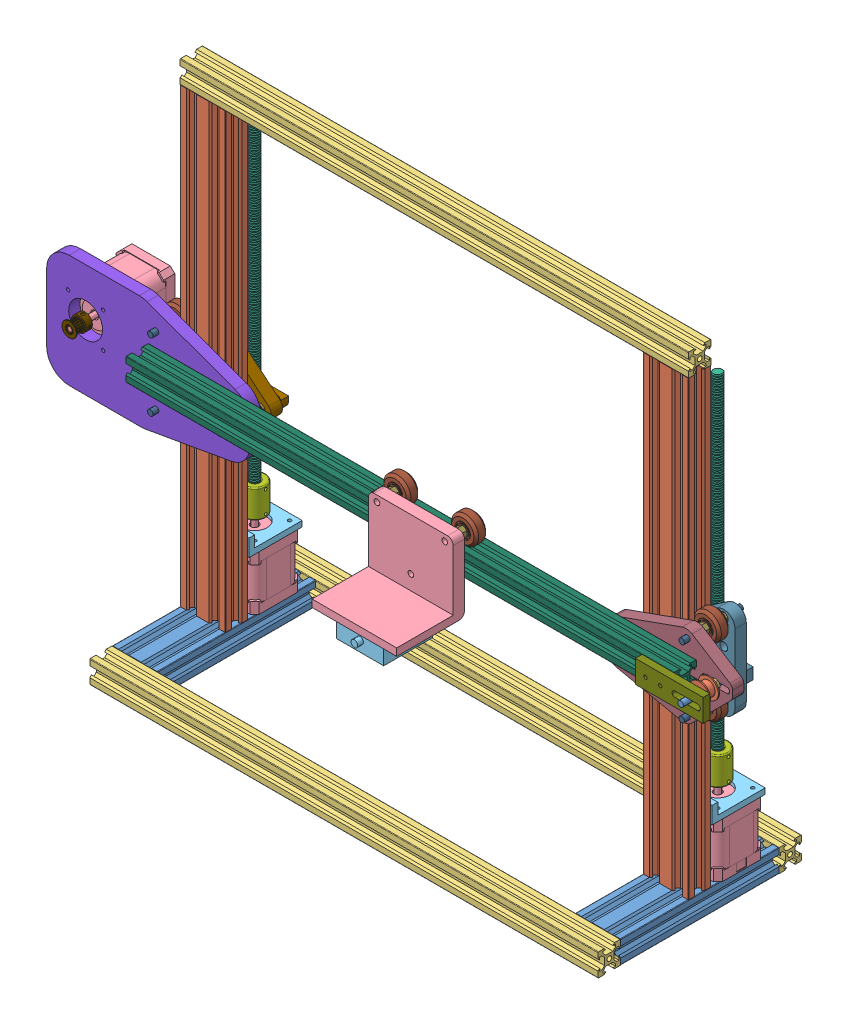
SolidWorks assembly Assembly_Design_1, configuration Default. Lengths in mm.
Overall size (607.25 440 192.3).
70 component instances, 26 part files, 187 mates.
Components (placement in the parent):
- V_Slot_40x20_140mm-1: V_Slot_40x20_140mm [Default] at (9.5 10 -140) x (0 -1 0) z (0 0 1) size (20 40 140)
- V_Slot_40x20_400mm-1: V_Slot_40x20_400mm [Default] at (9.5 420 -70) x (0 0 -1) z (0 -1 0) size (20 40 400)
- V_Slot_20x20_450mm-1: V_Slot_20x20_450mm [Default] at (-0.5 430 -70) x (0 0 -1) z (1 0 0) size (20 20 450)
- V_Slot_40x20_400mm-2: V_Slot_40x20_400mm [Default] at (419.5 20 -70) x (0 0 1) z (0 1 0) size (20 40 400)
- V_Slot_40x20_140mm-2: V_Slot_40x20_140mm [Default] at (439.5 10 -140) x (0 1 0) z (0 0 1) size (20 40 140)
- V_Slot_20x20_450mm-2: V_Slot_20x20_450mm [Default] at (449.5 10 10) x (0 0 1) z (-1 0 0) size (20 20 450)
- V_Slot_20x20_450mm-3: V_Slot_20x20_450mm [Default] at (-0.5 10 -150) x (0 0 -1) z (1 0 0) size (20 20 450)
- Stepper_Motor_17HS19-2004S1-1: Stepper_Motor_17HS19-2004S1 [Predeterminado] at (19.5 44 -106) x (1 0 0) z (0 1 0) size (42 42 72)
- stepper_motor_mounting_bracket-1: stepper_motor_mounting_bracket [Default] at (19.5 68 -106) x (-1 0 0) z (0 1 0) size (42 47 15)
- Stepper_Motor_17HS19-2004S1-2: Stepper_Motor_17HS19-2004S1 [Predeterminado] at (429.5 44 -106) x (-1 0 0) z (0 1 0) size (42 42 72)
- stepper_motor_mounting_bracket-2: stepper_motor_mounting_bracket [Default] at (429.5 68 -106) x (-1 0 0) z (0 1 0) size (42 47 15)
- LeadScrew 8mm x 2mmPitch-1: LeadScrew 8mm x 2mmPitch [Default] at (429.5 92 -106) x (0.998698 0 -0.051019) z (0 -1 0) size (9.24 8 303.06)
- Coupling_Shaft_5x8-1: Coupling_Shaft_5x8 [Default] at (429.5 79.5 -106) x (0.999828 0 -0.01857) z (0.01857 0 0.999828) size (19 25 19)
- LeadScrew 8mm x 2mmPitch-2: LeadScrew 8mm x 2mmPitch [Default] at (19.5 92 -106) x (1 0 0) z (0 -1 0) size (9.24 8 303.06)
- Coupling_Shaft_5x8-2: Coupling_Shaft_5x8 [Default] at (19.5 79.5 -106) x (0.999319 0 -0.036886) z (0.036886 0 0.999319) size (19 25 19)
- leftbeam_wheel_mount_front-2: leftbeam_wheel_mount_front [Default] at (-107.5 151.5377 -58.8) x (1 0 0) z (0 -1 0) size (180 10 100)
- Stepper_Motor_17HS19-2004S1-4: Stepper_Motor_17HS19-2004S1 [Predeterminado] at (-73 209.0377 -82.8) size (42 42 72)
- leftbeam_wheel_mount_back-2: leftbeam_wheel_mount_back [Default] at (-21 158.5012 -91) x (1 0 0) z (0 -1 0) size (80 40 83.06)
- Wheel_mount_rod_for_brackets-1: Wheel_mount_rod_for_brackets [Default] at (-10.7 231.5377 -96) x (-0.970108 -0.242673 0) z (-0.242673 0.970108 0) size (5 52.2 5)
- Wheel_mount_rod_for_brackets-2: Wheel_mount_rod_for_brackets [Default] at (-10.7 171.5377 -96) x (-0.232708 0.972547 0) z (0.972547 0.232708 0) size (5 52.2 5)
- Wheel_mount_rod_for_brackets-3: Wheel_mount_rod_for_brackets [Default] at (49.8 186.5377 -96) x (-0.732499 0.680769 0) z (0.680769 0.732499 0) size (5 52.2 5)
- V_Slot_Wheel_OD24xID5-1: V_Slot_Wheel_OD24xID5 [Default] at (-10.7 231.5377 -69.9) x (0.993327 -0.115336 0) z (0 0 1) size (24 24 10.2)
- M5 Hex nut-1: M5 Hex nut [Default] at (-10.7 231.5377 -61.8) x (0.939693 -0.34202 0) z (0.34202 0.939693 0) size (9.01 6.7 7.8)
- M5 Hex nut-2: M5 Hex nut [Default] at (-10.7 231.5377 -78) x (0.939693 -0.34202 0) z (-0.34202 -0.939693 0) size (9.01 6.7 7.8)
- M5 Hex nut-3: M5 Hex nut [Default] at (-10.7 171.5377 -61.8) x (0 -1 0) z (1 0 0) size (9.01 6.7 7.8)
- M5 Hex nut-4: M5 Hex nut [Default] at (-10.7 171.5377 -78) x (0 -1 0) z (1 0 0) size (9.01 6.7 7.8)
- V_Slot_Wheel_OD24xID5-2: V_Slot_Wheel_OD24xID5 [Default] at (-10.7 171.5377 -69.9) x (0.998331 -0.057756 0) z (0 0 1) size (24 24 10.2)
- M5 Hex nut-5: M5 Hex nut [Default] at (49.8 186.5377 -78) x (0.866025 -0.5 0) z (-0.5 -0.866025 0) size (9.01 6.7 7.8)
- M5 Hex nut-6: M5 Hex nut [Default] at (49.8 186.5377 -61.8) x (0.866025 -0.5 0) z (0.5 0.866025 0) size (9.01 6.7 7.8)
- V_Slot_Wheel_OD24xID5-3: V_Slot_Wheel_OD24xID5 [Default] at (49.8 186.5377 -69.9) x (0.999874 0.01588 0) z (0 0 1) size (24 24 10.2)
- rightbeam_wheel_mount_front-1: rightbeam_wheel_mount_front [Default] at (499.75 204.3878 -58.8) size (110 73.04 10)
- rightbeam_wheels_mount _back-1: rightbeam_wheels_mount _back [Default] at (469.75 209.0377 -91) size (80.5 81.06 40)
- Wheel_mount_rod_for_brackets-4: Wheel_mount_rod_for_brackets [Default] at (459.75 231.5377 -96) x (0.11149 -0.993766 0) z (-0.993766 -0.11149 0) size (5 52.2 5)
- Wheel_mount_rod_for_brackets-5: Wheel_mount_rod_for_brackets [Default] at (399.25 186.5377 -96) x (-0.923728 -0.383049 0) z (-0.383049 0.923728 0) size (5 52.2 5)
- Wheel_mount_rod_for_brackets-6: Wheel_mount_rod_for_brackets [Default] at (459.75 171.5377 -96) x (-0.923728 -0.383049 0) z (-0.383049 0.923728 0) size (5 52.2 5)
- M5 Hex nut-7: M5 Hex nut [Default] at (459.75 171.5377 -78) x (0.965926 -0.258819 0) z (-0.258819 -0.965926 0) size (9.01 6.7 7.8)
- M5 Hex nut-8: M5 Hex nut [Default] at (459.75 171.5377 -61.8) x (0.965926 -0.258819 0) z (-0.258819 -0.965926 0) size (9.01 6.7 7.8)
- M5 Hex nut-9: M5 Hex nut [Default] at (399.25 186.5377 -61.8) x (0.941742 0.336336 0) z (0.336336 -0.941742 0) size (9.01 6.7 7.8)
- M5 Hex nut-10: M5 Hex nut [Default] at (399.25 186.5377 -78) x (0.941742 0.336336 0) z (0.336336 -0.941742 0) size (9.01 6.7 7.8)
- M5 Hex nut-11: M5 Hex nut [Default] at (459.75 231.5377 -78) x (0.941742 0.336336 0) z (-0.336336 0.941742 0) size (9.01 6.7 7.8)
- M5 Hex nut-12: M5 Hex nut [Default] at (459.75 231.5377 -61.8) x (0.941742 0.336336 0) z (0.336336 -0.941742 0) size (9.01 6.7 7.8)
- V_Slot_Wheel_OD24xID5-4: V_Slot_Wheel_OD24xID5 [Default] at (459.75 231.5377 -69.9) x (0.615703 0.787979 0) z (0 0 1) size (24 24 10.2)
- V_Slot_Wheel_OD24xID5-5: V_Slot_Wheel_OD24xID5 [Default] at (459.75 171.5377 -69.9) x (0.637684 0.770298 0) z (0 0 1) size (24 24 10.2)
- V_Slot_Wheel_OD24xID5-6: V_Slot_Wheel_OD24xID5 [Default] at (399.25 186.5377 -69.9) x (0.99333 -0.115309 0) z (0 0 1) size (24 24 10.2)
- V_Slot_20x20_485-1: V_Slot_20x20_485 [Default] at (467.75 209.0377 -38.8) x (0 0 1) z (-1 0 0) size (20 20 485)
- right_pulley_wheel_mount-1: right_pulley_wheel_mount [Default] at (439.75 199.0377 -28.8) size (60 20 6)
- LeadScrew Nut 8mm x 2mmPitch-1: LeadScrew Nut 8mm x 2mmPitch [Default] at (429.5 166.4718 -106) x (-1 0 0) z (0 -1 0) size (22 22 16.05)
- LeadScrew Nut 8mm x 2mmPitch-2: LeadScrew Nut 8mm x 2mmPitch [Default] at (19.5 168.5012 -106) x (-1 0 0) z (0 -1 0) size (22 22 16.05)
- 16 teeth pulley GT2 6mm ASSEMBLY PART-1: 16 teeth pulley GT2 6mm ASSEMBLY PART [По умолчанию] at (-73.2117 209.4463 -27.2) x (-0.994801 0.101836 0) z (0 0 -1) size (13.17 13.17 14.1)
- 5x46mm_rod-1: 5x46mm_rod [Default] at (484.75 209.0377 -17.8) x (0.599612 0.800291 0) z (-0.800291 0.599612 0) size (5 46 5)
- POWGE 2GT idler 20T B5-1: POWGE 2GT idler 20T B5 [Default] at (484.75 209.0377 -38.8) x (0 0 1) z (0.346507 -0.938047 0) size (9 18 18)
- M5 Hex nut_5.5mm-1: M5 Hex nut_5.5mm [Default] at (484.75 209.0377 -31.55) x (1 0 0) z (0 1 0) size (9.01 6.2 7.8)
- M5 Hex nut_5.5mm-2: M5 Hex nut_5.5mm [Default] at (484.75 209.0377 -46.05) x (1 0 0) z (0 1 0) size (9.01 6.2 7.8)
- centre_laser_mount-1: centre_laser_mount [Default] at (246.0327 207.4577 -27.7) x (1 0 0) z (0 -1 0) size (75 60 65)
- V_Slot_Wheel_OD24xID5-7: V_Slot_Wheel_OD24xID5 [Default] at (276.0327 229.4577 -38.8) x (0.900063 0.43576 0) z (0 0 -1) size (24 24 10.2)
- V_Slot_Wheel_OD24xID5-8: V_Slot_Wheel_OD24xID5 [Default] at (216.0327 229.4577 -38.8) x (0.900063 0.43576 0) z (0 0 -1) size (24 24 10.2)
- V_Slot_Wheel_OD24xID5-9: V_Slot_Wheel_OD24xID5 [Default] at (246.0327 189.4577 -38.8) x (0.900063 0.43576 0) z (0 0 -1) size (24 24 10.2)
- M5 Hex nut-13: M5 Hex nut [Default] at (216.0327 229.4577 -30.7) x (0 -1 0) z (1 0 0) size (9.01 6.7 7.8)
- M5 Hex nut-14: M5 Hex nut [Default] at (246.0327 189.4577 -30.7) x (0 -1 0) z (1 0 0) size (9.01 6.7 7.8)
- M5 Hex nut-15: M5 Hex nut [Default] at (276.0327 229.4577 -30.7) x (0 1 0) z (1 0 0) size (9.01 6.7 7.8)
- heavy hex flange screw_am-2: heavy hex flange screw_am [PreviewCfg] at (246.0327 189.4577 -49.7) x (0 0 1) z (0.383049 -0.923728 0) size (40.8 11.8 11.8) (hidden)
- heavy hex flange screw_am-3: heavy hex flange screw_am [PreviewCfg] at (276.0327 229.4577 -49.7) x (0 0 1) z (0.383049 -0.923728 0) size (40.8 11.8 11.8) (hidden)
- heavy hex flange screw_am-4: heavy hex flange screw_am [PreviewCfg] at (216.0327 229.4577 -49.7) x (0 0 1) z (0.383049 -0.923728 0) size (40.8 11.8 11.8) (hidden)
- flat washer regular_am-1: flat washer regular_am [PreviewCfg] at (246.0327 189.4577 -17.7) x (0 0 -1) z (0.380789 -0.924662 0) size (1.75 15 15) (hidden)
- flat washer regular_am-2: flat washer regular_am [PreviewCfg] at (276.0327 229.4577 -17.7) x (0 0 -1) z (0.383049 -0.923728 0) size (1.75 15 15) (hidden)
- flat washer regular_am-3: flat washer regular_am [PreviewCfg] at (216.0327 229.4577 -17.7) x (0 0 -1) z (0.383049 -0.923728 0) size (1.75 15 15) (hidden)
- hex flange nut_am-1: hex flange nut_am [PreviewCfg] at (276.0327 229.4577 -10.95) x (0.923728 0.383049 0) z (0 0 1) size (11.8 11.8 5) (hidden)
- hex flange nut_am-2: hex flange nut_am [PreviewCfg] at (246.0327 189.4577 -10.95) x (0.923728 0.383049 0) z (0 0 1) size (11.8 11.8 5) (hidden)
- hex flange nut_am-3: hex flange nut_am [PreviewCfg] at (216.0327 229.4577 -10.95) x (0.923728 0.383049 0) z (0 0 1) size (11.8 11.8 5) (hidden)
- SEN0366_DFRobot_makeshift-1: SEN0366_DFRobot_makeshift [Default] at (225.0327 151.9577 -15.7) x (0 0 1) z (-1 0 0) size (48 18 42)
Mates (geometry in assembly coordinates):
- Coincident5: coincident: point of V_Slot_40x20_140mm-1
- Parallel1: parallel anti-aligned: plane of V_Slot_40x20_140mm-1 through (9.5 0 0) normal (0 -1 0)
- Parallel2: parallel aligned: plane of V_Slot_40x20_140mm-1 through (39.5 10 0) normal (1 0 0)
- Coincident12: coincident anti-aligned: plane of V_Slot_40x20_140mm-1 through (9.5 20 0) normal (0 1 0); plane of V_Slot_40x20_400mm-1 through (9.5 20 -70) normal (0 -1 0)
- Parallel5: parallel aligned: plane of V_Slot_40x20_140mm-1 through (-0.5 10 0) normal (-1 0 0); plane of V_Slot_40x20_400mm-1 through (-0.5 20 -70) normal (-1 0 0)
- Coincident15: coincident aligned: plane of V_Slot_40x20_140mm-1 through (-0.5 10 0) normal (-1 0 0); plane of V_Slot_40x20_400mm-1 through (-0.5 20 -70) normal (-1 0 0)
- Distance2: distance = 60 mm aligned: plane of V_Slot_40x20_400mm-1 through (9.5 20 -80) normal (0 0 -1); plane of V_Slot_40x20_140mm-1 through (9.5 10 -140) normal (0 0 -1)
- Coincident17: coincident anti-aligned: plane of V_Slot_40x20_400mm-1 through (9.5 420 -70) normal (0 1 0); plane of V_Slot_20x20_450mm-1 through (449.5 420 -65.42) normal (0 -1 0)
- Parallel6: parallel anti-aligned: plane of V_Slot_40x20_400mm-1 through (-0.5 20 -70) normal (-1 0 0); plane of V_Slot_20x20_450mm-1 through (449.5 439.5 -79.5) normal (1 0 0)
- Coincident19: coincident aligned: plane of V_Slot_40x20_400mm-1 through (-0.5 20 -70) normal (-1 0 0); plane of V_Slot_20x20_450mm-1 through (-0.5 439.5 -79.5) normal (-1 0 0)
- Coincident20: coincident aligned: plane of V_Slot_40x20_400mm-1 through (9.5 20 -80) normal (0 0 -1); plane of V_Slot_20x20_450mm-1 through (449.5 420.5 -80) normal (0 0 -1)
- Coincident21: coincident anti-aligned: plane of V_Slot_20x20_450mm-1 through (449.5 420 -65.42) normal (0 -1 0); plane of V_Slot_40x20_400mm-2 through (419.5 420 -70) normal (0 1 0)
- Parallel7: parallel anti-aligned: plane of V_Slot_20x20_450mm-1 through (449.5 439.5 -79.5) normal (1 0 0); plane of V_Slot_40x20_400mm-2 through (409.5 420 -70) normal (-1 0 0)
- Coincident23: coincident aligned: plane of V_Slot_20x20_450mm-1 through (449.5 439.5 -79.5) normal (1 0 0); plane of V_Slot_40x20_400mm-2 through (449.5 420 -70) normal (1 0 0)
- Coincident24: coincident aligned: plane of V_Slot_20x20_450mm-1 through (449.5 420.5 -60) normal (0 0 1); plane of V_Slot_40x20_400mm-2 through (419.5 420 -60) normal (0 0 1)
- Coincident25: coincident anti-aligned: plane of V_Slot_40x20_400mm-2 through (419.5 20 -70) normal (0 -1 0); plane of V_Slot_40x20_140mm-2 through (439.5 20 0) normal (0 1 0)
- Coincident26: coincident aligned: plane of V_Slot_40x20_400mm-2 through (409.5 420 -70) normal (-1 0 0); plane of V_Slot_40x20_140mm-2 through (409.5 10 0) normal (-1 0 0)
- Distance3: distance = 60 mm aligned: plane of V_Slot_40x20_400mm-2 through (419.5 420 -80) normal (0 0 -1); plane of V_Slot_40x20_140mm-2 through (439.5 10 -140) normal (0 0 -1)
- Coincident28: coincident anti-aligned: plane of V_Slot_40x20_140mm-2 through (439.5 10 0) normal (0 0 1); plane of V_Slot_20x20_450mm-2 through (-0.5 19.5 0) normal (0 0 -1)
- Coincident29: coincident aligned: plane of V_Slot_40x20_140mm-1 through (-0.5 10 0) normal (-1 0 0); plane of V_Slot_20x20_450mm-2 through (-0.5 19.5 19.5) normal (-1 0 0)
- Coincident30: coincident aligned: plane of V_Slot_40x20_140mm-1 through (9.5 20 0) normal (0 1 0); plane of V_Slot_20x20_450mm-2 through (-0.5 20 5.42) normal (0 1 0)
- Coincident31: coincident anti-aligned: plane of V_Slot_40x20_140mm-2 through (439.5 10 -140) normal (0 0 -1); plane of V_Slot_20x20_450mm-3 through (449.5 19.5 -140) normal (0 0 1)
- Coincident32: coincident aligned: plane of V_Slot_40x20_140mm-2 through (449.5 10 0) normal (1 0 0); plane of V_Slot_20x20_450mm-3 through (449.5 19.5 -159.5) normal (1 0 0)
- Coincident33: coincident aligned: plane of V_Slot_40x20_140mm-2 through (439.5 20 0) normal (0 1 0); plane of V_Slot_20x20_450mm-3 through (449.5 20 -145.42) normal (0 1 0)
- Coincident34: coincident anti-aligned: plane of V_Slot_40x20_140mm-1 through (9.5 20 0) normal (0 1 0); plane of Stepper_Motor_17HS19-2004S1-1 through (19.5 20 -106) normal (0 -1 0)
- Parallel8: parallel aligned: plane of V_Slot_40x20_140mm-1 through (-0.5 10 0) normal (-1 0 0); plane of Stepper_Motor_17HS19-2004S1-1 through (-1.5 68 -123) normal (-1 0 0)
- Coincident36: coincident anti-aligned: plane of Stepper_Motor_17HS19-2004S1-1 through (19.5 68 -106) normal (0 1 0); plane of stepper_motor_mounting_bracket-1 through (19.5 68 -106) normal (0 -1 0)
- Concentric1: concentric aligned: circle of Stepper_Motor_17HS19-2004S1-1; circle of stepper_motor_mounting_bracket-1
- Coincident38: coincident anti-aligned: plane of V_Slot_40x20_400mm-1 through (9.5 20 -80) normal (0 0 -1); plane of stepper_motor_mounting_bracket-1 through (40.5 73 -80) normal (0 0 1)
- Distance4: distance = 1 mm aligned: plane of stepper_motor_mounting_bracket-1 through (40.5 73 -85) normal (1 0 0); plane of V_Slot_40x20_400mm-1 through (39.5 20 -70) normal (1 0 0)
- Coincident40: coincident anti-aligned: plane of V_Slot_40x20_140mm-2 through (439.5 20 0) normal (0 1 0); plane of Stepper_Motor_17HS19-2004S1-2 through (429.5 20 -106) normal (0 -1 0)
- Parallel9: parallel anti-aligned: plane of V_Slot_40x20_400mm-2 through (419.5 420 -80) normal (0 0 -1); plane of Stepper_Motor_17HS19-2004S1-2 through (412.5 68 -85) normal (0 0 1)
- Coincident42: coincident anti-aligned: plane of Stepper_Motor_17HS19-2004S1-2 through (429.5 68 -106) normal (0 1 0); plane of stepper_motor_mounting_bracket-2 through (429.5 68 -106) normal (0 -1 0)
- Concentric2: concentric aligned: circle of Stepper_Motor_17HS19-2004S1-2; circle of stepper_motor_mounting_bracket-2
- Coincident44: coincident anti-aligned: plane of V_Slot_40x20_400mm-2 through (419.5 420 -80) normal (0 0 -1); plane of stepper_motor_mounting_bracket-2 through (450.5 73 -80) normal (0 0 1)
- Distance5: distance = 1 mm aligned: plane of stepper_motor_mounting_bracket-2 through (450.5 73 -85) normal (1 0 0); plane of V_Slot_40x20_400mm-2 through (449.5 420 -70) normal (1 0 0)
- Concentric3: concentric aligned: cylinder of Stepper_Motor_17HS19-2004S1-2 through (429.5 92 -106) axis (0 -1 0) radius 2.5; cylinder of Coupling_Shaft_5x8-1 through (429.5 104.5 -106) axis (0 -1 0) radius 2.5
- Coincident46: coincident aligned: plane of Stepper_Motor_17HS19-2004S1-2 through (429.5 92 -106) normal (0 1 0); plane of Coupling_Shaft_5x8-1 through (429.5 92 -106) normal (0 1 0)
- Lock1: lock: unknown of stepper_motor_mounting_bracket-2; unknown of Coupling_Shaft_5x8-1
- Concentric4: concentric anti-aligned: cylinder of LeadScrew 8mm x 2mmPitch-1 through (429.5 392 -106) axis (0 -1 0) radius 4; cylinder of Coupling_Shaft_5x8-1 through (429.5 92 -106) axis (0 1 0) radius 4
- Coincident47: coincident anti-aligned: plane of LeadScrew 8mm x 2mmPitch-1 through (429.5 92 -106) normal (0 -1 0); plane of Coupling_Shaft_5x8-1 through (429.5 92 -106) normal (0 1 0)
- Lock2: lock: unknown of LeadScrew 8mm x 2mmPitch-1; unknown of Coupling_Shaft_5x8-1
- Concentric5: concentric aligned: cylinder of Stepper_Motor_17HS19-2004S1-1 through (19.5 92 -106) axis (0 -1 0) radius 2.5; cylinder of Coupling_Shaft_5x8-2 through (19.5 104.5 -106) axis (0 -1 0) radius 2.5
- Coincident48: coincident aligned: plane of Stepper_Motor_17HS19-2004S1-1 through (19.5 92 -106) normal (0 1 0); plane of Coupling_Shaft_5x8-2 through (19.5 92 -106) normal (0 1 0)
- Lock3: lock: unknown of stepper_motor_mounting_bracket-1; unknown of Coupling_Shaft_5x8-2
- Coincident49: coincident anti-aligned: plane of LeadScrew 8mm x 2mmPitch-2 through (19.5 92 -106) normal (0 -1 0); plane of Coupling_Shaft_5x8-2 through (19.5 92 -106) normal (0 1 0)
- Concentric6: concentric anti-aligned: cylinder of LeadScrew 8mm x 2mmPitch-2 through (19.5 392 -106) axis (0 -1 0) radius 4; cylinder of Coupling_Shaft_5x8-2 through (19.5 92 -106) axis (0 1 0) radius 4
- Lock4: lock: unknown of LeadScrew 8mm x 2mmPitch-2; unknown of Coupling_Shaft_5x8-2
- Parallel15: parallel anti-aligned: plane of V_Slot_40x20_400mm-1 through (9.5 20 -60) normal (0 0 1); plane of leftbeam_wheel_mount_front-2 through (-107.5 151.5377 -58.8) normal (0 0 -1)
- Concentric13: concentric aligned: cylinder of leftbeam_wheel_mount_front-2 through (-73 209.0377 -48.8) axis (0 0 -1) radius 15; cylinder of Stepper_Motor_17HS19-2004S1-4 through (-73 209.0377 -34.8) axis (0 0 -1) radius 2.5
- Parallel16: parallel aligned: plane of leftbeam_wheel_mount_front-2 through (-107.5 151.5377 -48.8) normal (-1 0 0); plane of Stepper_Motor_17HS19-2004S1-4 through (-94 209.0377 -106.802) normal (-1 0 0)
- Concentric14: concentric anti-aligned: cylinder of LeadScrew 8mm x 2mmPitch-2 through (19.5 392 -106) axis (0 -1 0) radius 4; cylinder of leftbeam_wheel_mount_back-2 through (19.5 158.5012 -106) axis (0 1 0) radius 5.25
- Concentric15: concentric aligned: circle of leftbeam_wheel_mount_front-2; circle of leftbeam_wheel_mount_back-2
- Concentric16: concentric anti-aligned: cylinder of Wheel_mount_rod_for_brackets-1 through (-10.7 231.5377 -43.8) axis (0 0 -1) radius 2.5; cylinder of V_Slot_Wheel_OD24xID5-1 through (-10.7 231.5377 -75) axis (0 0 1) radius 2.5
- Concentric17: concentric aligned: circle of leftbeam_wheel_mount_front-2; circle of leftbeam_wheel_mount_back-2
- Concentric18: concentric anti-aligned: cylinder of Wheel_mount_rod_for_brackets-1 through (-10.7 231.5377 -43.8) axis (0 0 -1) radius 2.5; circle of M5 Hex nut-1
- Coincident67: coincident anti-aligned: plane of V_Slot_Wheel_OD24xID5-1 through (-10.7 231.5377 -64.8) normal (0 0 1); plane of M5 Hex nut-1 through (-10.7 231.5377 -64.8) normal (0 0 -1)
- Concentric20: concentric anti-aligned: cylinder of Wheel_mount_rod_for_brackets-1 through (-10.7 231.5377 -43.8) axis (0 0 -1) radius 2.5; circle of M5 Hex nut-2
- Coincident69: coincident anti-aligned: plane of V_Slot_Wheel_OD24xID5-1 through (-10.7 231.5377 -75) normal (0 0 -1); plane of M5 Hex nut-2 through (-10.7 231.5377 -75) normal (0 0 1)
- Coincident70: coincident anti-aligned: plane of leftbeam_wheel_mount_front-2 through (-107.5 151.5377 -58.8) normal (0 0 -1); plane of M5 Hex nut-1 through (-10.7 231.5377 -58.8) normal (0 0 1)
- Parallel17: parallel aligned: plane of M5 Hex nut-1 through (-11.482 235.9727 -64.8) normal (0.34202 0.939693 0); plane of M5 Hex nut-2 through (-7.2502 234.4324 -75) normal (0.34202 0.939693 0)
- Parallel18: parallel aligned: plane of leftbeam_wheel_mount_front-2 through (-65.3464 267.3537 -48.8) normal (0.34202 0.939693 0); plane of M5 Hex nut-2 through (-7.2502 234.4324 -75) normal (0.34202 0.939693 0)
- Coincident73: coincident anti-aligned: plane of leftbeam_wheel_mount_back-2 through (53 185.2686 -81) normal (0 0 1); plane of M5 Hex nut-2 through (-10.7 231.5377 -81) normal (0 0 -1)
- Concentric21: concentric aligned: circle of leftbeam_wheel_mount_front-2; circle of Wheel_mount_rod_for_brackets-2
- Concentric22: concentric aligned: circle of leftbeam_wheel_mount_front-2; circle of Wheel_mount_rod_for_brackets-3
- Concentric23: concentric aligned: circle of leftbeam_wheel_mount_front-2; circle of Wheel_mount_rod_for_brackets-1
- Concentric24: concentric anti-aligned: cylinder of Wheel_mount_rod_for_brackets-2 through (-10.7 171.5377 -43.8) axis (0 0 -1) radius 2.5; cylinder of V_Slot_Wheel_OD24xID5-2 through (-10.7 171.5377 -75) axis (0 0 1) radius 2.5
- Concentric26: concentric aligned: cone of leftbeam_wheel_mount_back-2; cone of M5 Hex nut-4 through (-10.7 171.5377 -80.84) axis (0 0 1)
- Coincident78: coincident anti-aligned: plane of leftbeam_wheel_mount_back-2 through (53 185.2686 -81) normal (0 0 1); plane of M5 Hex nut-4 through (-10.7 171.5377 -81) normal (0 0 -1)
- Coincident79: coincident anti-aligned: plane of M5 Hex nut-4 through (-10.7 171.5377 -75) normal (0 0 1); plane of V_Slot_Wheel_OD24xID5-2 through (-10.7 171.5377 -75) normal (0 0 -1)
- Concentric27: concentric anti-aligned: circle of leftbeam_wheel_mount_front-2; circle of M5 Hex nut-3
- Coincident81: coincident anti-aligned: plane of leftbeam_wheel_mount_front-2 through (-107.5 151.5377 -58.8) normal (0 0 -1); plane of M5 Hex nut-3 through (-10.7 171.5377 -58.8) normal (0 0 1)
- Parallel19: parallel aligned: plane of M5 Hex nut-3 through (-6.8 173.7894 -64.8) normal (1 0 0); plane of M5 Hex nut-4 through (-6.8 173.7894 -81) normal (1 0 0)
- Parallel20: parallel anti-aligned: plane of leftbeam_wheel_mount_back-2 through (-21 164.5012 -81) normal (-1 0 0); plane of M5 Hex nut-4 through (-6.8 173.7894 -81) normal (1 0 0)
- Concentric28: concentric anti-aligned: cylinder of Wheel_mount_rod_for_brackets-3 through (49.8 186.5377 -43.8) axis (0 0 -1) radius 2.5; cylinder of V_Slot_Wheel_OD24xID5-3 through (49.8 186.5377 -75) axis (0 0 1) radius 2.5
- Concentric29: concentric anti-aligned: cylinder of Wheel_mount_rod_for_brackets-3 through (49.8 186.5377 -43.8) axis (0 0 -1) radius 2.5; circle of M5 Hex nut-5
- Coincident85: coincident anti-aligned: plane of M5 Hex nut-5 through (49.8 186.5377 -75) normal (0 0 1); plane of V_Slot_Wheel_OD24xID5-3 through (49.8 186.5377 -75) normal (0 0 -1)
- Coincident86: coincident anti-aligned: plane of leftbeam_wheel_mount_back-2 through (53 185.2686 -81) normal (0 0 1); plane of M5 Hex nut-5 through (49.8 186.5377 -81) normal (0 0 -1)
- Concentric30: concentric anti-aligned: circle of leftbeam_wheel_mount_front-2; circle of M5 Hex nut-6
- Coincident87: coincident anti-aligned: plane of leftbeam_wheel_mount_front-2 through (-107.5 151.5377 -58.8) normal (0 0 -1); plane of M5 Hex nut-6 through (49.8 186.5377 -58.8) normal (0 0 1)
- Parallel21: parallel aligned: plane of M5 Hex nut-5 through (53.7 184.2861 -75) normal (1 0 0); plane of M5 Hex nut-6 through (53.7 188.7894 -64.8) normal (1 0 0)
- Parallel22: parallel aligned: plane of leftbeam_wheel_mount_front-2 through (72.5 151.5377 -48.8) normal (1 0 0); plane of M5 Hex nut-6 through (53.7 188.7894 -64.8) normal (1 0 0)
- Distance6: distance = 5 mm aligned: plane of Wheel_mount_rod_for_brackets-1 through (-10.7 231.5377 -96) normal (0 0 -1); plane of leftbeam_wheel_mount_back-2 through (53 185.2686 -91) normal (0 0 -1)
- Distance8: distance = 5 mm aligned: plane of Wheel_mount_rod_for_brackets-2 through (-10.7 171.5377 -96) normal (0 0 -1); plane of leftbeam_wheel_mount_back-2 through (53 185.2686 -91) normal (0 0 -1)
- Distance9: distance = 5 mm aligned: plane of Wheel_mount_rod_for_brackets-3 through (49.8 186.5377 -96) normal (0 0 -1); plane of leftbeam_wheel_mount_back-2 through (53 185.2686 -91) normal (0 0 -1)
- Coincident90: coincident aligned: plane of leftbeam_wheel_mount_front-2 through (-107.5 151.5377 -48.8) normal (0 0 1); plane of rightbeam_wheel_mount_front-1 through (458.5548 228.3423 -48.8) normal (0 0 1)
- Concentric31: concentric anti-aligned: cylinder of LeadScrew 8mm x 2mmPitch-1 through (429.5 392 -106) axis (0 -1 0) radius 4; cylinder of rightbeam_wheels_mount _back-1 through (429.5 156.4718 -106) axis (0 1 0) radius 5.25
- Parallel25: parallel anti-aligned: plane of rightbeam_wheel_mount_front-1 through (458.5548 228.3423 -58.8) normal (0 0 -1); plane of rightbeam_wheels_mount _back-1 through (408.25 163.7006 -81) normal (0 0 1)
- Concentric32: concentric aligned: cylinder of rightbeam_wheel_mount_front-1 through (459.75 231.5377 -48.8) axis (0 0 -1) radius 2.5; cylinder of rightbeam_wheels_mount _back-1 through (459.75 231.5377 -81) axis (0 0 -1) radius 2.5
- Concentric33: concentric aligned: cylinder of rightbeam_wheel_mount_front-1 through (459.75 171.5377 -48.8) axis (0 0 -1) radius 2.5; cylinder of rightbeam_wheels_mount _back-1 through (459.75 171.5377 -81) axis (0 0 -1) radius 2.5
- Concentric34: concentric aligned: cylinder of rightbeam_wheel_mount_front-1 through (399.25 186.5377 -48.8) axis (0 0 -1) radius 2.5; cylinder of rightbeam_wheels_mount _back-1 through (399.25 186.5377 -81) axis (0 0 -1) radius 2.5
- Concentric35: concentric aligned: circle of rightbeam_wheel_mount_front-1; circle of Wheel_mount_rod_for_brackets-4
- Distance10: distance = 5 mm aligned: plane of Wheel_mount_rod_for_brackets-4 through (459.75 231.5377 -43.8) normal (0 0 1); plane of rightbeam_wheel_mount_front-1 through (458.5548 228.3423 -48.8) normal (0 0 1)
- Concentric36: concentric aligned: circle of rightbeam_wheel_mount_front-1; circle of Wheel_mount_rod_for_brackets-6
- Distance11: distance = 5 mm aligned: plane of Wheel_mount_rod_for_brackets-6 through (459.75 171.5377 -96) normal (0 0 -1); plane of rightbeam_wheels_mount _back-1 through (408.25 163.7006 -91) normal (0 0 -1)
- Concentric37: concentric aligned: circle of rightbeam_wheel_mount_front-1; circle of Wheel_mount_rod_for_brackets-5
- Distance12: distance = 5 mm aligned: plane of Wheel_mount_rod_for_brackets-5 through (399.25 186.5377 -96) normal (0 0 -1); plane of rightbeam_wheels_mount _back-1 through (408.25 163.7006 -91) normal (0 0 -1)
- Concentric38: concentric anti-aligned: circle of rightbeam_wheel_mount_front-1; circle of M5 Hex nut-11
- Coincident99: coincident anti-aligned: plane of rightbeam_wheels_mount _back-1 through (408.25 163.7006 -81) normal (0 0 1); plane of M5 Hex nut-11 through (459.75 231.5377 -81) normal (0 0 -1)
- Concentric39: concentric anti-aligned: cylinder of Wheel_mount_rod_for_brackets-4 through (459.75 231.5377 -43.8) axis (0 0 -1) radius 2.5; cylinder of V_Slot_Wheel_OD24xID5-4 through (459.75 231.5377 -75) axis (0 0 1) radius 2.5
- Coincident100: coincident anti-aligned: plane of M5 Hex nut-11 through (459.75 231.5377 -75) normal (0 0 1); plane of V_Slot_Wheel_OD24xID5-4 through (459.75 231.5377 -75) normal (0 0 -1)
- Concentric40: concentric anti-aligned: circle of rightbeam_wheel_mount_front-1; circle of M5 Hex nut-12
- Coincident101: coincident anti-aligned: plane of rightbeam_wheel_mount_front-1 through (458.5548 228.3423 -58.8) normal (0 0 -1); plane of M5 Hex nut-12 through (459.75 231.5377 -58.8) normal (0 0 1)
- Concentric41: concentric anti-aligned: circle of rightbeam_wheel_mount_front-1; circle of M5 Hex nut-7
- Coincident102: coincident anti-aligned: plane of rightbeam_wheels_mount _back-1 through (408.25 163.7006 -81) normal (0 0 1); plane of M5 Hex nut-7 through (459.75 171.5377 -81) normal (0 0 -1)
- Concentric42: concentric anti-aligned: cylinder of Wheel_mount_rod_for_brackets-6 through (459.75 171.5377 -43.8) axis (0 0 -1) radius 2.5; cylinder of V_Slot_Wheel_OD24xID5-5 through (459.75 171.5377 -75) axis (0 0 1) radius 2.5
- Coincident103: coincident anti-aligned: plane of M5 Hex nut-7 through (459.75 171.5377 -75) normal (0 0 1); plane of V_Slot_Wheel_OD24xID5-5 through (459.75 171.5377 -75) normal (0 0 -1)
- Concentric43: concentric anti-aligned: circle of rightbeam_wheel_mount_front-1; circle of M5 Hex nut-8
- Coincident104: coincident anti-aligned: plane of rightbeam_wheel_mount_front-1 through (458.5548 228.3423 -58.8) normal (0 0 -1); plane of M5 Hex nut-8 through (459.75 171.5377 -58.8) normal (0 0 1)
- Concentric44: concentric anti-aligned: circle of rightbeam_wheel_mount_front-1; circle of M5 Hex nut-10
- Coincident105: coincident anti-aligned: plane of rightbeam_wheels_mount _back-1 through (408.25 163.7006 -81) normal (0 0 1); plane of M5 Hex nut-10 through (399.25 186.5377 -81) normal (0 0 -1)
- Concentric45: concentric anti-aligned: cylinder of Wheel_mount_rod_for_brackets-5 through (399.25 186.5377 -43.8) axis (0 0 -1) radius 2.5; cylinder of V_Slot_Wheel_OD24xID5-6 through (399.25 186.5377 -75) axis (0 0 1) radius 2.5
- Coincident106: coincident anti-aligned: plane of M5 Hex nut-10 through (399.25 186.5377 -75) normal (0 0 1); plane of V_Slot_Wheel_OD24xID5-6 through (399.25 186.5377 -75) normal (0 0 -1)
- Concentric46: concentric anti-aligned: circle of rightbeam_wheel_mount_front-1; circle of M5 Hex nut-9
- Coincident107: coincident anti-aligned: plane of rightbeam_wheel_mount_front-1 through (458.5548 228.3423 -58.8) normal (0 0 -1); plane of M5 Hex nut-9 through (399.25 186.5377 -58.8) normal (0 0 1)
- Parallel26: parallel aligned: plane of M5 Hex nut-9 through (400.0588 190.9679 -58.8) normal (-0.336336 0.941742 0); plane of M5 Hex nut-10 through (400.0588 190.9679 -75) normal (-0.336336 0.941742 0)
- Parallel27: parallel aligned: plane of rightbeam_wheel_mount_front-1 through (455.1914 237.7598 -48.8) normal (-0.336336 0.941742 0); plane of M5 Hex nut-9 through (400.0588 190.9679 -58.8) normal (-0.336336 0.941742 0)
- Parallel28: parallel aligned: plane of M5 Hex nut-11 through (456.3178 234.4532 -81) normal (-0.336336 0.941742 0); plane of M5 Hex nut-12 through (460.5588 235.9679 -58.8) normal (-0.336336 0.941742 0)
- Parallel29: parallel aligned: plane of rightbeam_wheel_mount_front-1 through (455.1914 237.7598 -48.8) normal (-0.336336 0.941742 0); plane of M5 Hex nut-11 through (456.3178 234.4532 -81) normal (-0.336336 0.941742 0)
- Parallel30: parallel aligned: plane of M5 Hex nut-7 through (460.9155 167.1879 -75) normal (0.707107 -0.707107 0); plane of M5 Hex nut-8 through (460.9155 167.1879 -58.8) normal (0.707107 -0.707107 0)
- Parallel31: parallel aligned: plane of rightbeam_wheel_mount_front-1 through (463.5969 168.2347 -48.8) normal (0.707107 -0.707107 0); plane of M5 Hex nut-8 through (460.9155 167.1879 -58.8) normal (0.707107 -0.707107 0)
- Coincident114: coincident anti-aligned: plane of leftbeam_wheel_mount_front-2 through (-107.5 151.5377 -48.8) normal (0 0 1); plane of V_Slot_20x20_485-1 through (-17.25 218.5377 -48.8) normal (0 0 -1)
- Concentric47: concentric anti-aligned: circle of leftbeam_wheel_mount_front-2; circle of V_Slot_20x20_485-1
- Concentric48: concentric anti-aligned: circle of rightbeam_wheel_mount_front-1; circle of V_Slot_20x20_485-1
- Parallel32: parallel aligned: plane of leftbeam_wheel_mount_front-2 through (-107.5 151.5377 -48.8) normal (0 0 1); plane of V_Slot_20x20_485-1 through (-17.25 218.5377 -28.8) normal (0 0 1)
- Parallel33: parallel anti-aligned: plane of rightbeam_wheel_mount_front-1 through (458.5548 228.3423 -48.8) normal (0 0 1); plane of right_pulley_wheel_mount-1 through (439.75 199.0377 -28.8) normal (0 0 -1)
- Parallel34: parallel aligned: plane of V_Slot_20x20_485-1 through (-17.25 219.0377 -43.38) normal (0 1 0); plane of right_pulley_wheel_mount-1 through (439.75 219.0377 -22.8) normal (0 1 0)
- Concentric49: concentric aligned: circle of rightbeam_wheel_mount_front-1; circle of right_pulley_wheel_mount-1
- Coincident125: coincident anti-aligned: plane of V_Slot_20x20_485-1 through (-17.25 218.5377 -28.8) normal (0 0 1); plane of right_pulley_wheel_mount-1 through (439.75 199.0377 -28.8) normal (0 0 -1)
- Concentric50: concentric aligned: cylinder of LeadScrew 8mm x 2mmPitch-1 through (429.5 392 -106) axis (0 -1 0) radius 4; cylinder of LeadScrew Nut 8mm x 2mmPitch-1 through (429.5 179.9718 -106) axis (0 -1 0) radius 4
- Coincident126: coincident anti-aligned: plane of rightbeam_wheels_mount _back-1 through (445.75 166.4718 -121) normal (0 1 0); plane of LeadScrew Nut 8mm x 2mmPitch-1 through (429.5 166.4718 -106) normal (0 -1 0)
- Concentric51: concentric anti-aligned: circle of rightbeam_wheels_mount _back-1; circle of LeadScrew Nut 8mm x 2mmPitch-1
- Concentric52: concentric anti-aligned: circle of rightbeam_wheels_mount _back-1; circle of LeadScrew Nut 8mm x 2mmPitch-1
- Concentric53: concentric aligned: cylinder of LeadScrew 8mm x 2mmPitch-2 through (19.5 392 -106) axis (0 -1 0) radius 4; cylinder of LeadScrew Nut 8mm x 2mmPitch-2 through (19.5 182.0012 -106) axis (0 -1 0) radius 4
- Coincident129: coincident anti-aligned: plane of leftbeam_wheel_mount_back-2 through (53 168.5012 -121) normal (0 1 0); plane of LeadScrew Nut 8mm x 2mmPitch-2 through (19.5 168.5012 -106) normal (0 -1 0)
- Concentric54: concentric aligned: circle of leftbeam_wheel_mount_back-2; circle of LeadScrew Nut 8mm x 2mmPitch-2
- Concentric55: concentric aligned: circle of leftbeam_wheel_mount_back-2; circle of LeadScrew Nut 8mm x 2mmPitch-2
- Parallel37: parallel anti-aligned: plane of right_pulley_wheel_mount-1 through (439.75 199.0377 -22.8) normal (0 0 1); plane of 5x46mm_rod-1 through (484.75 209.0377 -63.8) normal (0 0 -1)
- Tangent2: tangent anti-aligned: plane of right_pulley_wheel_mount-1 through (474.75 206.5377 -22.8) normal (0 1 0); cylinder of 5x46mm_rod-1 through (484.75 209.0377 -63.8) axis (0 0 1) radius 2.5
- Distance15: distance = 5 mm aligned: plane of 5x46mm_rod-1 through (484.75 209.0377 -17.8) normal (0 0 1); plane of right_pulley_wheel_mount-1 through (439.75 199.0377 -22.8) normal (0 0 1)
- Distance16: distance = 10 mm: cylinder of 5x46mm_rod-1 through (484.75 209.0377 -63.8) axis (0 0 1) radius 2.5; cylinder of right_pulley_wheel_mount-1 through (474.75 209.0377 -22.8) axis (0 0 -1) radius 2.5
- Concentric59: concentric aligned: cylinder of Stepper_Motor_17HS19-2004S1-4 through (-73 209.0377 -34.8) axis (0 0 -1) radius 2.5; cylinder of 16 teeth pulley GT2 6mm ASSEMBLY PART-1 through (-73 209.0377 -34.25) axis (0 0 -1) radius 2.5
- Distance17: distance = 0.425 mm: plane of 16 teeth pulley GT2 6mm ASSEMBLY PART-1 through (-73 209.0377 -42.35) normal (0 0 1); line of V_Slot_20x20_485-1 through (-17.25 217.5827 -41.925) axis (1 0 0)
- Lock5: lock: unknown of Stepper_Motor_17HS19-2004S1-4; unknown of 16 teeth pulley GT2 6mm ASSEMBLY PART-1
- Concentric61: concentric anti-aligned: cylinder of 5x46mm_rod-1 through (484.75 209.0377 -63.8) axis (0 0 1) radius 2.5; cylinder of POWGE 2GT idler 20T B5-1 through (484.75 209.0377 -36.55) axis (0 0 -1) radius 2.5
- Distance18: distance = 0.375 mm: plane of POWGE 2GT idler 20T B5-1 through (487.3618 201.9672 -35.3) normal (0 0 -1); line of V_Slot_20x20_485-1 through (-17.25 217.5827 -35.675) axis (1 0 0)
- Concentric62: concentric anti-aligned: cylinder of 5x46mm_rod-1 through (484.75 209.0377 -63.8) axis (0 0 1) radius 2.5; circle of M5 Hex nut_5.5mm-1
- Coincident139: coincident anti-aligned: plane of POWGE 2GT idler 20T B5-1 through (487.0889 202.7059 -34.3) normal (0 0 1); plane of M5 Hex nut_5.5mm-1 through (484.75 209.0377 -34.3) normal (0 0 -1)
- Concentric63: concentric aligned: cylinder of 5x46mm_rod-1 through (484.75 209.0377 -63.8) axis (0 0 1) radius 2.5; circle of M5 Hex nut_5.5mm-2
- Coincident140: coincident anti-aligned: plane of POWGE 2GT idler 20T B5-1 through (487.0889 202.7059 -43.3) normal (0 0 -1); plane of M5 Hex nut_5.5mm-2 through (484.75 209.0377 -43.3) normal (0 0 1)
- Concentric64: concentric anti-aligned: circle of centre_laser_mount-1; circle of M5 Hex nut-13
- Coincident141: coincident anti-aligned: plane of centre_laser_mount-1 through (246.0327 207.4577 -27.7) normal (0 0 -1); plane of M5 Hex nut-13 through (216.0327 229.4577 -27.7) normal (0 0 1)
- Concentric65: concentric anti-aligned: circle of V_Slot_Wheel_OD24xID5-8; circle of M5 Hex nut-13
- Coincident142: coincident anti-aligned: plane of V_Slot_Wheel_OD24xID5-8 through (216.0327 229.4577 -33.7) normal (0 0 1); plane of M5 Hex nut-13 through (216.0327 229.4577 -33.7) normal (0 0 -1)
- Concentric66: concentric anti-aligned: circle of centre_laser_mount-1; circle of M5 Hex nut-15
- Coincident143: coincident anti-aligned: plane of centre_laser_mount-1 through (246.0327 207.4577 -27.7) normal (0 0 -1); plane of M5 Hex nut-15 through (276.0327 229.4577 -27.7) normal (0 0 1)
- Concentric67: concentric anti-aligned: circle of V_Slot_Wheel_OD24xID5-7; circle of M5 Hex nut-15
- Coincident144: coincident anti-aligned: plane of V_Slot_Wheel_OD24xID5-7 through (276.0327 229.4577 -33.7) normal (0 0 1); plane of M5 Hex nut-15 through (276.0327 229.4577 -33.7) normal (0 0 -1)
- Concentric68: concentric anti-aligned: circle of centre_laser_mount-1; circle of M5 Hex nut-14
- Coincident145: coincident anti-aligned: plane of centre_laser_mount-1 through (246.0327 207.4577 -27.7) normal (0 0 -1); plane of M5 Hex nut-14 through (246.0327 189.4577 -27.7) normal (0 0 1)
- Concentric69: concentric anti-aligned: circle of V_Slot_Wheel_OD24xID5-9; circle of M5 Hex nut-14
- Coincident146: coincident anti-aligned: plane of V_Slot_Wheel_OD24xID5-9 through (246.0327 189.4577 -33.7) normal (0 0 1); plane of M5 Hex nut-14 through (246.0327 189.4577 -33.7) normal (0 0 -1)
- Concentric70: concentric aligned: cylinder of V_Slot_Wheel_OD24xID5-9 through (246.0327 189.4577 -33.7) axis (0 0 -1) radius 2.5; cylinder of heavy hex flange screw_am-2 through (246.0327 189.4577 -49.7) axis (0 0 -1) radius 2.5
- Coincident147: coincident anti-aligned: plane of V_Slot_Wheel_OD24xID5-9 through (246.0327 189.4577 -43.9) normal (0 0 -1); plane of heavy hex flange screw_am-2 through (241.7662 187.6885 -43.9) normal (0 0 1)
- Concentric71: concentric aligned: cylinder of V_Slot_Wheel_OD24xID5-7 through (276.0327 229.4577 -33.7) axis (0 0 -1) radius 2.5; cylinder of heavy hex flange screw_am-3 through (276.0327 229.4577 -49.7) axis (0 0 -1) radius 2.5
- Coincident148: coincident anti-aligned: plane of V_Slot_Wheel_OD24xID5-7 through (276.0327 229.4577 -43.9) normal (0 0 -1); plane of heavy hex flange screw_am-3 through (271.7662 227.6885 -43.9) normal (0 0 1)
- Concentric72: concentric aligned: cylinder of V_Slot_Wheel_OD24xID5-8 through (216.0327 229.4577 -33.7) axis (0 0 -1) radius 2.5; cylinder of heavy hex flange screw_am-4 through (216.0327 229.4577 -49.7) axis (0 0 -1) radius 2.5
- Coincident149: coincident anti-aligned: plane of V_Slot_Wheel_OD24xID5-8 through (216.0327 229.4577 -43.9) normal (0 0 -1); plane of heavy hex flange screw_am-4 through (211.7662 227.6885 -43.9) normal (0 0 1)
- Concentric73: concentric anti-aligned: cylinder of heavy hex flange screw_am-2 through (246.0327 189.4577 -49.7) axis (0 0 -1) radius 2.5; cylinder of flat washer regular_am-1 through (246.0327 189.4577 17.225) axis (0 0 1) radius 2.89
- Coincident150: coincident anti-aligned: plane of centre_laser_mount-1 through (246.0327 207.4577 -17.7) normal (0 0 1); plane of flat washer regular_am-1 through (248.705 190.5582 -17.7) normal (0 0 -1)
- Concentric74: concentric anti-aligned: cylinder of heavy hex flange screw_am-3 through (276.0327 229.4577 -49.7) axis (0 0 -1) radius 2.5; cylinder of flat washer regular_am-2 through (276.0327 229.4577 17.225) axis (0 0 1) radius 2.89
- Coincident151: coincident anti-aligned: plane of centre_laser_mount-1 through (246.0327 207.4577 -17.7) normal (0 0 1); plane of flat washer regular_am-2 through (278.7023 230.5648 -17.7) normal (0 0 -1)
- Concentric75: concentric anti-aligned: cylinder of heavy hex flange screw_am-4 through (216.0327 229.4577 -49.7) axis (0 0 -1) radius 2.5; cylinder of flat washer regular_am-3 through (216.0327 229.4577 17.225) axis (0 0 1) radius 2.89
- Coincident152: coincident anti-aligned: plane of centre_laser_mount-1 through (246.0327 207.4577 -17.7) normal (0 0 1); plane of flat washer regular_am-3 through (218.7023 230.5648 -17.7) normal (0 0 -1)
- Concentric76: concentric anti-aligned: cylinder of heavy hex flange screw_am-3 through (276.0327 229.4577 -49.7) axis (0 0 -1) radius 2.5; cylinder of hex flange nut_am-1 through (276.0327 229.4577 -35.9875) axis (0 0 1) radius 2.5
- Coincident153: coincident anti-aligned: plane of flat washer regular_am-2 through (282.9607 232.3306 -15.95) normal (0 0 1); plane of hex flange nut_am-1 through (274.2635 233.7243 -15.95) normal (0 0 -1)
- Concentric77: concentric anti-aligned: cylinder of heavy hex flange screw_am-2 through (246.0327 189.4577 -49.7) axis (0 0 -1) radius 2.5; cylinder of hex flange nut_am-2 through (246.0327 189.4577 -35.9875) axis (0 0 1) radius 2.5
- Coincident154: coincident anti-aligned: plane of flat washer regular_am-1 through (252.9677 192.3137 -15.95) normal (0 0 1); plane of hex flange nut_am-2 through (244.2635 193.7243 -15.95) normal (0 0 -1)
- Concentric78: concentric anti-aligned: cylinder of heavy hex flange screw_am-4 through (216.0327 229.4577 -49.7) axis (0 0 -1) radius 2.5; cylinder of hex flange nut_am-3 through (216.0327 229.4577 -35.9875) axis (0 0 1) radius 2.5
- Coincident155: coincident anti-aligned: plane of flat washer regular_am-3 through (222.9607 232.3306 -15.95) normal (0 0 1); plane of hex flange nut_am-3 through (214.2635 233.7243 -15.95) normal (0 0 -1)
- Parallel38: parallel aligned: plane of V_Slot_20x20_485-1 through (-17.25 218.5377 -28.8) normal (0 0 1); plane of centre_laser_mount-1 through (246.0327 207.4577 -17.7) normal (0 0 1)
- Parallel39: parallel anti-aligned: plane of V_Slot_20x20_485-1 through (-17.25 219.0377 -34.22) normal (0 1 0); plane of centre_laser_mount-1 through (208.5327 169.9577 32.3) normal (0 -1 0)
- Distance19: distance = 1.975 mm: plane of V_Slot_Wheel_OD24xID5-8 through (216.0327 229.4577 -33.7) normal (0 0 1); line of V_Slot_20x20_485-1 through (-17.25 217.5827 -35.675) axis (1 0 0)
- Tangent5: tangent anti-aligned: plane of V_Slot_20x20_485-1 through (-17.25 217.5827 -35.675) normal (0 0.707107 -0.707107); cone of V_Slot_Wheel_OD24xID5-8 through (216.0327 229.4577 -35.8) axis (0 0 1)
- Coincident159: coincident anti-aligned: plane of centre_laser_mount-1 through (208.5327 169.9577 32.3) normal (0 -1 0); plane of SEN0366_DFRobot_makeshift-1 through (225.0327 169.9577 -15.7) normal (0 1 0)
- Coincident161: coincident aligned: plane of centre_laser_mount-1 through (246.0327 207.4577 32.3) normal (0 0 1); plane of SEN0366_DFRobot_makeshift-1 through (225.0327 169.9577 32.3) normal (0 0 1)
- Distance20: distance = 16.5 mm aligned: plane of SEN0366_DFRobot_makeshift-1 through (225.0327 169.9577 -15.7) normal (-1 0 0); plane of centre_laser_mount-1 through (208.5327 179.9577 -17.7) normal (-1 0 0)
